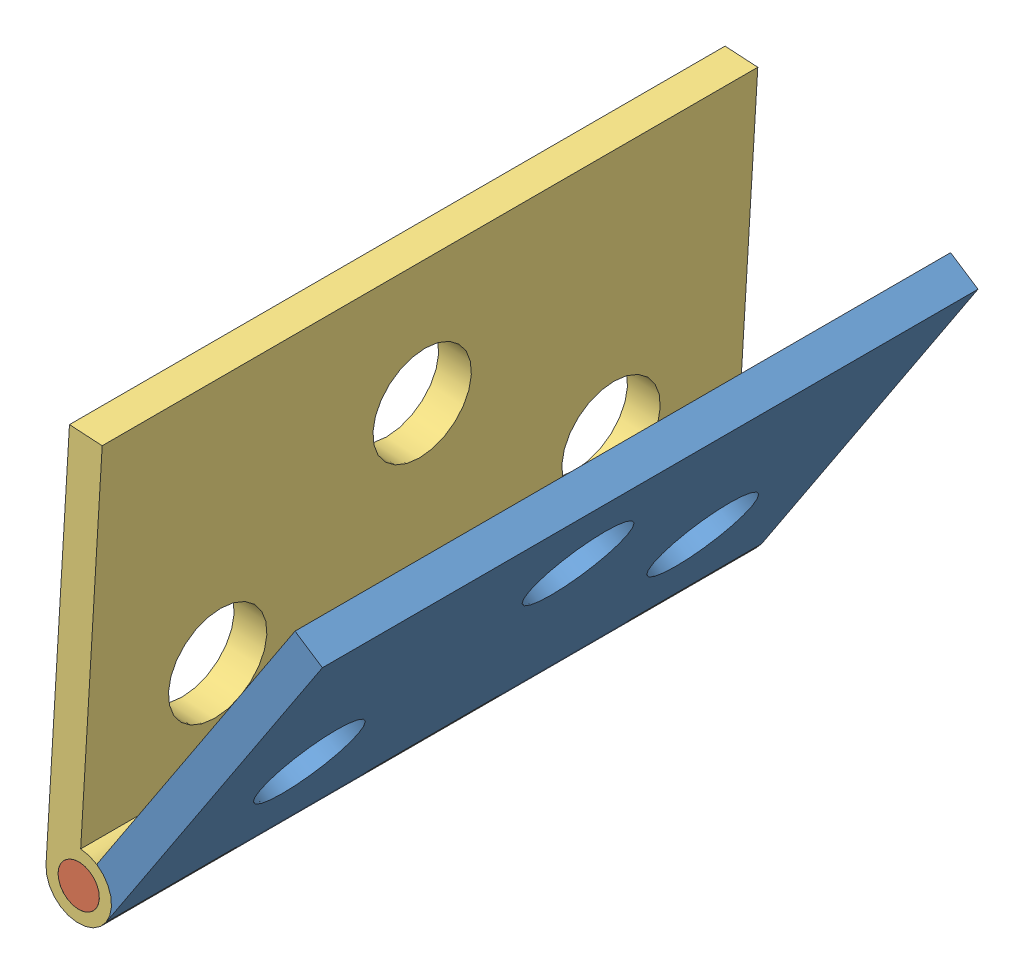
SolidWorks assembly Hinje_Joint, configuration Default. Lengths in mm.
Overall size (22.05 33.56 50).
3 component instances, 3 part files, 6 mates.
Components (placement in the parent):
- HInge_1-1: HInge_1 [Default] at (-26.4023 35.172 17.4655) x (-0.835227 0.549905 0) z (0 0 1) size (5 32.5 50)
- PIn-1: PIn [Default] at (-44.9875 11.4899 -32.5345) x (0 0 1) z (-1 0 0) size (50 3.15 3.15)
- HInge_2-1: HInge_2 [Default] at (-45.693 41.5856 -32.5345) x (0.998218 -0.059669 0) z (0 0 -1) size (5 32.5 50)
Mates (geometry in assembly coordinates):
- Coincident1: coincident anti-aligned: axis of HInge_1-1 through (-44.9875 11.4899 7.4655) axis (0 0 -1); axis of HInge_2-1 through (-44.9875 11.4899 7.4655) axis (0 0 1)
- Coincident3: coincident anti-aligned: axis of HInge_1-1 through (-44.9875 11.4899 -22.5345) axis (0 0 -1); axis of HInge_2-1 through (-44.9875 11.4899 7.4655) axis (0 0 1)
- Coincident4: coincident aligned: plane of HInge_1-1 through (-28.4904 36.5467 17.4655) normal (0 0 1); plane of HInge_2-1 through (-43.1975 41.4364 17.4655) normal (0 0 1)
- Coincident6: coincident anti-aligned: axis of PIn-1 through (-44.9875 11.4899 17.4655) axis (0 0 -1); axis of HInge_2-1 through (-44.9875 11.4899 7.4655) axis (0 0 1)
- Coincident7: coincident aligned: plane of PIn-1 through (-44.9875 11.4899 -32.5345) normal (0 0 -1); plane of HInge_2-1 through (-43.1975 41.4364 -32.5345) normal (0 0 -1)
- LimitAngle2: limit planar angle = 2.619047 rad aligned: plane of HInge_1-1 through (-28.4904 36.5467 17.4655) normal (-0.835227 0.549905 0); plane of HInge_2-1 through (-43.1975 41.4364 -32.5345) normal (0.998218 -0.059669 0)
